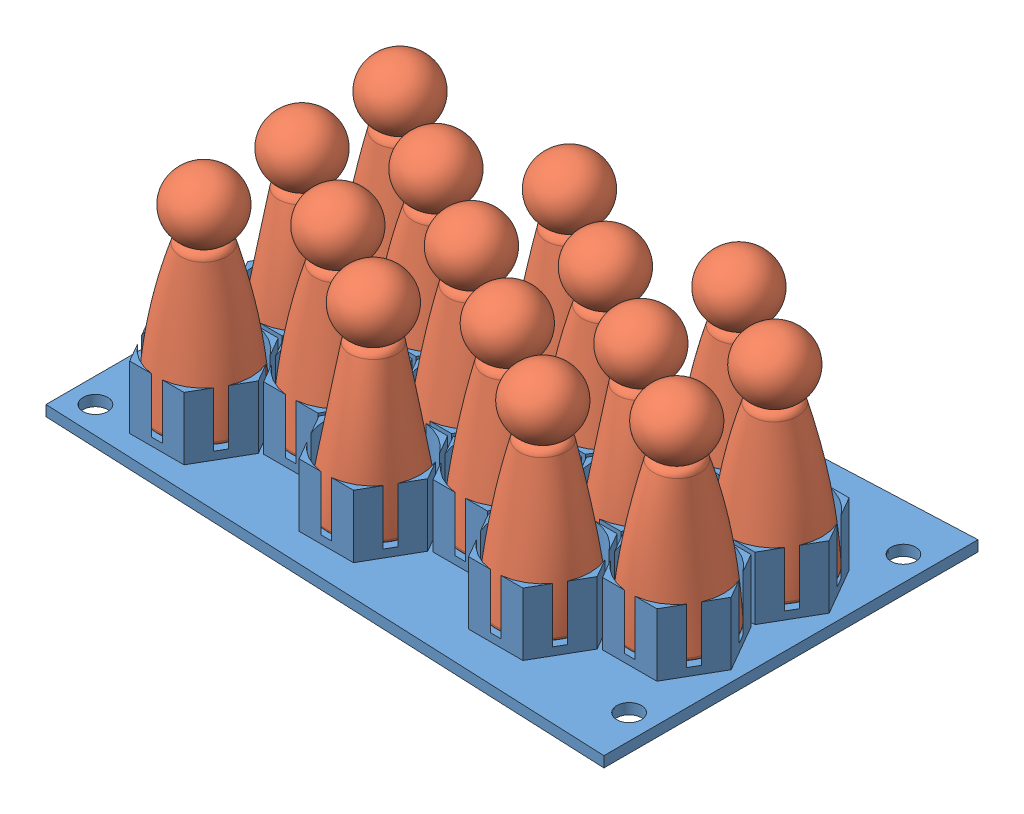
SolidWorks assembly Passenger_Payload, configuration Default. Lengths in mm.
Overall size (236 93.2 151.4).
16 component instances, 2 part files, 29 mates.
Components (placement in the parent):
- updated_hex_passenger_flooring-1: updated_hex_passenger_flooring [Default] at (147.2714 129.3547 119.4389) size (236 29.7 151.4)
- paitent piece.-2: paitent piece. [Default] at (238.9018 131.5047 139.2826) x (0.264485 0 -0.96439) z (0.96439 0 0.264485) size (38.1 88.9 39.09)
- paitent piece.-3: paitent piece. [Default] at (204.5314 131.5047 79.7514) x (0.992654 0 -0.120989) z (0.120989 0 0.992654) size (38.1 88.9 39.09)
- paitent piece.-4: paitent piece. [Default] at (204.5314 131.5047 159.1264) x (0.99632 0 0.085706) z (-0.085706 0 0.99632) size (38.1 88.9 39.09)
- paitent piece.-5: paitent piece. [Default] at (170.3218 131.5047 99.5951) x (0.972213 0 -0.2341) z (0.2341 0 0.972213) size (38.1 88.9 39.09)
- paitent piece.-6: paitent piece. [Default] at (170.3218 131.5047 139.2826) x (0.984298 0 0.176517) z (-0.176517 0 0.984298) size (38.1 88.9 39.09)
- paitent piece.-7: paitent piece. [Default] at (135.9514 131.5047 159.1264) x (0.637529 0 0.770426) z (-0.770426 0 0.637529) size (38.1 88.9 39.09)
- paitent piece.-8: paitent piece. [Default] at (135.9514 131.5047 119.4389) x (0.982701 0 0.185197) z (-0.185197 0 0.982701) size (38.1 88.9 39.09)
- paitent piece.-9: paitent piece. [Default] at (204.5314 131.5047 119.4389) x (0.697216 0 0.716861) z (-0.716861 0 0.697216) size (38.1 88.9 39.09)
- paitent piece.-11: paitent piece. [Default] at (238.9018 131.5047 99.5951) x (0.935969 0 -0.352084) z (0.352084 0 0.935969) size (38.1 88.9 39.09)
- paitent piece.-12: paitent piece. [Default] at (101.7418 131.5047 99.5951) x (0.974182 0 -0.225762) z (0.225762 0 0.974182) size (38.1 88.9 39.09)
- paitent piece.-13: paitent piece. [Default] at (67.3714 131.5047 79.7514) x (0.980204 0 0.197989) z (-0.197989 0 0.980204) size (38.1 88.9 39.09)
- paitent piece.-14: paitent piece. [Default] at (67.3714 131.5047 159.1264) x (0.892352 0 -0.451341) z (0.451341 0 0.892352) size (38.1 88.9 39.09)
- paitent piece.-15: paitent piece. [Default] at (67.3714 131.5047 119.4389) x (0.60258 0 0.798058) z (-0.798058 0 0.60258) size (38.1 88.9 39.09)
- paitent piece.-16: paitent piece. [Default] at (135.9514 131.5047 79.7514) x (0.929812 0 0.368035) z (-0.368035 0 0.929812) size (38.1 88.9 39.09)
- paitent piece.-17: paitent piece. [Default] at (101.7418 131.5047 139.2826) x (0.983933 0 -0.178537) z (0.178537 0 0.983933) size (38.1 88.9 39.09)
Mates (geometry in assembly coordinates):
- Concentric1: concentric: cylinder of updated_hex_passenger_flooring-1 through (67.3714 131.5047 159.1264) axis (0 1 0) radius 14.351; cylinder of paitent piece.-14 through (67.3714 136.2672 159.1264) axis (0 -1 0) radius 12.7
- Concentric2: concentric: cylinder of updated_hex_passenger_flooring-1 through (67.3714 131.5047 119.4389) axis (0 1 0) radius 14.351; cylinder of paitent piece.-15 through (67.3714 136.2672 119.4389) axis (0 -1 0) radius 12.7
- Concentric3: concentric: cylinder of updated_hex_passenger_flooring-1 through (67.3714 131.5047 79.7514) axis (0 1 0) radius 14.351; cylinder of paitent piece.-13 through (67.3714 136.2672 79.7514) axis (0 -1 0) radius 12.7
- Concentric4: concentric: circle of updated_hex_passenger_flooring-1; cylinder of paitent piece.-12 through (101.7418 136.2672 99.5951) axis (0 -1 0) radius 12.7
- Concentric5: concentric: cylinder of updated_hex_passenger_flooring-1 through (101.7418 131.5047 139.2826) axis (0 1 0) radius 14.351; cylinder of paitent piece.-17 through (101.7418 136.2672 139.2826) axis (0 -1 0) radius 12.7
- Concentric6: concentric: cylinder of updated_hex_passenger_flooring-1 through (135.9514 131.5047 79.7514) axis (0 1 0) radius 14.351; cylinder of paitent piece.-16 through (135.9514 136.2672 79.7514) axis (0 -1 0) radius 12.7
- Concentric7: concentric: cylinder of updated_hex_passenger_flooring-1 through (135.9514 131.5047 119.4389) axis (0 1 0) radius 14.351; cylinder of paitent piece.-8 through (135.9514 136.2672 119.4389) axis (0 -1 0) radius 12.7
- Concentric8: concentric: cylinder of updated_hex_passenger_flooring-1 through (135.9514 131.5047 159.1264) axis (0 1 0) radius 14.351; cylinder of paitent piece.-7 through (135.9514 136.2672 159.1264) axis (0 -1 0) radius 12.7
- Concentric9: concentric: cylinder of updated_hex_passenger_flooring-1 through (170.3218 131.5047 139.2826) axis (0 1 0) radius 14.351; cylinder of paitent piece.-6 through (170.3218 136.2672 139.2826) axis (0 -1 0) radius 12.7
- Concentric10: concentric: cylinder of updated_hex_passenger_flooring-1 through (170.3218 131.5047 99.5951) axis (0 1 0) radius 14.351; cylinder of paitent piece.-5 through (170.3218 136.2672 99.5951) axis (0 -1 0) radius 12.7
- Concentric11: concentric: cylinder of updated_hex_passenger_flooring-1 through (204.5314 131.5047 159.1264) axis (0 1 0) radius 14.351; cylinder of paitent piece.-4 through (204.5314 136.2672 159.1264) axis (0 -1 0) radius 12.7
- Concentric12: concentric: cylinder of updated_hex_passenger_flooring-1 through (204.5314 131.5047 119.4389) axis (0 1 0) radius 14.351; cylinder of paitent piece.-9 through (204.5314 136.2672 119.4389) axis (0 -1 0) radius 12.7
- Concentric13: concentric: cylinder of updated_hex_passenger_flooring-1 through (204.5314 131.5047 79.7514) axis (0 1 0) radius 14.351; cylinder of paitent piece.-3 through (204.5314 136.2672 79.7514) axis (0 -1 0) radius 12.7
- Concentric14: concentric: cylinder of updated_hex_passenger_flooring-1 through (238.9018 131.5047 139.2826) axis (0 1 0) radius 14.351; cylinder of paitent piece.-2 through (238.9018 227.1376 139.2826) axis (0 -1 0) radius 12.7
- Concentric15: concentric: cylinder of updated_hex_passenger_flooring-1 through (238.9018 131.5047 99.5951) axis (0 1 0) radius 14.351; cylinder of paitent piece.-11 through (238.9018 230.5493 99.5951) axis (0 -1 0) radius 12.7
- Coincident1: coincident aligned: plane of paitent piece.-13 through (67.3714 131.5047 79.7514) normal (0 -1 0); circle of updated_hex_passenger_flooring-1
- Coincident2: coincident anti-aligned: plane of paitent piece.-14 through (67.3714 131.5047 159.1264) normal (0 -1 0); plane of updated_hex_passenger_flooring-1 through (67.3714 131.5047 159.1264) normal (0 1 0)
- Coincident3: coincident anti-aligned: plane of updated_hex_passenger_flooring-1 through (101.7418 131.5047 139.2826) normal (0 1 0); plane of paitent piece.-17 through (101.7418 131.5047 139.2826) normal (0 -1 0)
- Coincident4: coincident anti-aligned: plane of updated_hex_passenger_flooring-1 through (101.7418 131.5047 99.5951) normal (0 1 0); plane of paitent piece.-12 through (101.7418 131.5047 99.5951) normal (0 -1 0)
- Coincident5: coincident anti-aligned: plane of updated_hex_passenger_flooring-1 through (135.9514 131.5047 79.7514) normal (0 1 0); plane of paitent piece.-16 through (135.9514 131.5047 79.7514) normal (0 -1 0)
- Coincident6: coincident anti-aligned: plane of updated_hex_passenger_flooring-1 through (135.9514 131.5047 119.4389) normal (0 1 0); plane of paitent piece.-8 through (135.9514 131.5047 119.4389) normal (0 -1 0)
- Coincident7: coincident anti-aligned: plane of updated_hex_passenger_flooring-1 through (135.9514 131.5047 159.1264) normal (0 1 0); plane of paitent piece.-7 through (135.9514 131.5047 159.1264) normal (0 -1 0)
- Coincident8: coincident anti-aligned: plane of updated_hex_passenger_flooring-1 through (170.3218 131.5047 139.2826) normal (0 1 0); plane of paitent piece.-6 through (170.3218 131.5047 139.2826) normal (0 -1 0)
- Coincident9: coincident anti-aligned: plane of updated_hex_passenger_flooring-1 through (170.3218 131.5047 99.5951) normal (0 1 0); plane of paitent piece.-5 through (170.3218 131.5047 99.5951) normal (0 -1 0)
- Coincident10: coincident anti-aligned: plane of updated_hex_passenger_flooring-1 through (204.5314 131.5047 79.7514) normal (0 1 0); plane of paitent piece.-3 through (204.5314 131.5047 79.7514) normal (0 -1 0)
- Coincident11: coincident anti-aligned: plane of updated_hex_passenger_flooring-1 through (204.5314 131.5047 119.4389) normal (0 1 0); plane of paitent piece.-9 through (204.5314 131.5047 119.4389) normal (0 -1 0)
- Coincident12: coincident anti-aligned: plane of updated_hex_passenger_flooring-1 through (204.5314 131.5047 159.1264) normal (0 1 0); plane of paitent piece.-4 through (204.5314 131.5047 159.1264) normal (0 -1 0)
- Coincident13: coincident anti-aligned: plane of updated_hex_passenger_flooring-1 through (238.9018 131.5047 139.2826) normal (0 1 0); plane of paitent piece.-2 through (238.9018 131.5047 139.2826) normal (0 -1 0)
- Coincident14: coincident anti-aligned: plane of updated_hex_passenger_flooring-1 through (238.9018 131.5047 99.5951) normal (0 1 0); plane of paitent piece.-11 through (238.9018 131.5047 99.5951) normal (0 -1 0)
